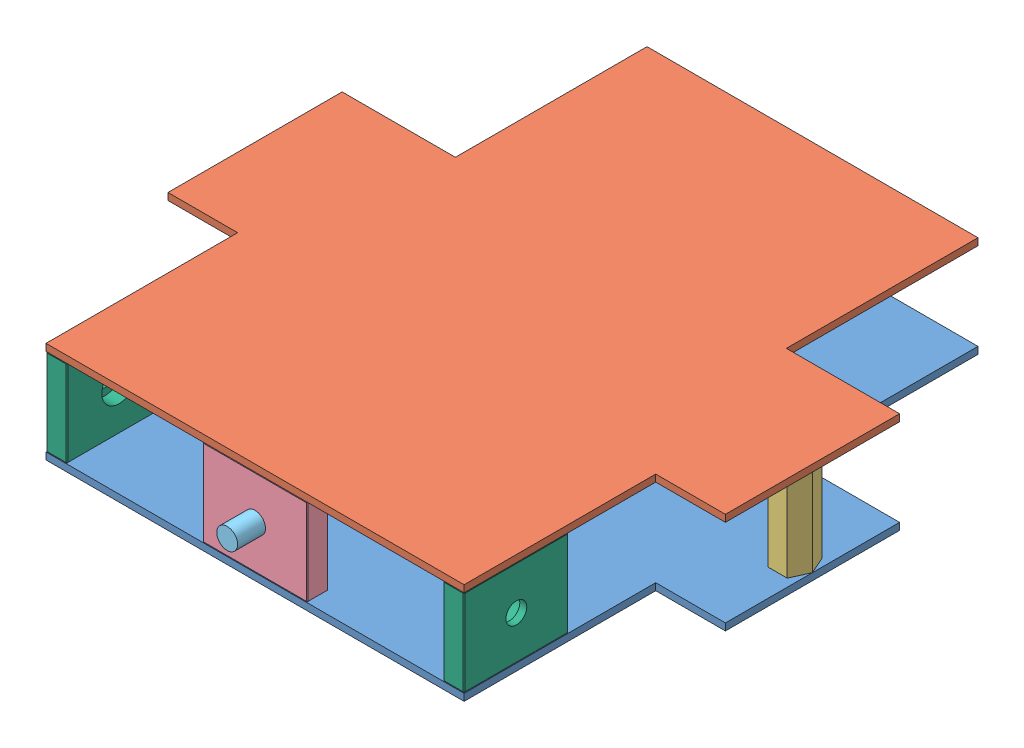
SolidWorks assembly modulo, configuration Default. Lengths in mm.
Overall size (160 29 176).
10 component instances, 6 part files, 25 mates.
Components (placement in the parent):
- chassi_inf-5: chassi_inf [Default] at origin size (160 2 160)
- chassi_sup-5: chassi_sup [Default] at (0 27 0) size (160 2 160)
- espacadores-2: espacadores [Default] at (75 2 0) size (10 25 10)
- apoio_acopolamento-1: apoio_acopolamento [Default] at (0 2 77) size (30 25 6)
- apoio_acopolamento-2: apoio_acopolamento [Default] at (0 2 -77) x (-1 0 0) z (0 0 -1) size (30 25 6)
- espacadores-5: espacadores [Default] at (-75 2 0) size (10 25 10)
- apoio_acopolamento2-1: apoio_acopolamento2 [Default] at (0 14.5 -78) x (0.923728 0.383049 0) z (-0.383049 0.923728 0) size (10 14 10)
- apoio_acopolamento2-2: apoio_acopolamento2 [Default] at (0 14.5 78) x (0.923728 0.383049 0) z (0.383049 -0.923728 0) size (10 14 10)
- apoio_rolamento1-1: apoio_rolamento1 [Default] at (-57 27 65) x (0 0 -1) z (-1 0 0) size (30 25 6)
- apoio_rolamento1-2: apoio_rolamento1 [Default] at (57 27 65) x (0 0 1) z (1 0 0) size (30 25 6)
Mates (geometry in assembly coordinates):
- Coincident39: coincident aligned: plane of chassi_inf-5 through (-47.5 2 -80) normal (0 0 -1); plane of apoio_acopolamento-2 through (15 27 -80) normal (0 0 -1)
- Coincident40: coincident anti-aligned: plane of chassi_inf-5 through (-47.5 2 -25) normal (0 1 0); plane of apoio_acopolamento-2 through (15 2 -80) normal (0 -1 0)
- Coincident41: coincident anti-aligned: plane of chassi_inf-5 through (-47.5 2 -25) normal (0 1 0); plane of espacadores-2 through (67.7429 2 -5) normal (0 -1 0)
- Coincident42: coincident anti-aligned: plane of chassi_inf-5 through (-47.5 2 -25) normal (0 1 0); plane of apoio_acopolamento-1 through (-15 2 80) normal (0 -1 0)
- Coincident43: coincident aligned: plane of chassi_inf-5 through (-60 2 80) normal (0 0 1); plane of apoio_acopolamento-1 through (-15 27 80) normal (0 0 1)
- Width1: width: plane of apoio_acopolamento-1 through (-15 27 74) normal (-1 0 0); plane of apoio_acopolamento-1 through (15 27 74) normal (1 0 0); plane of chassi_inf-5 through (60 2 25) normal (1 0 0); plane of chassi_inf-5 through (-60 2 25) normal (-1 0 0)
- Coincident44: coincident aligned: plane of apoio_acopolamento-1 through (15 27 74) normal (1 0 0); plane of apoio_acopolamento-2 through (15 27 -74) normal (1 0 0)
- Coincident45: coincident anti-aligned: plane of chassi_inf-5 through (-47.5 2 -25) normal (0 1 0); plane of espacadores-5 through (-82.2571 2 -5) normal (0 -1 0)
- Coincident46: coincident anti-aligned: plane of chassi_sup-5 through (-47.5 27 -25) normal (0 -1 0); plane of apoio_acopolamento-2 through (15 27 -80) normal (0 1 0)
- Coincident47: coincident aligned: plane of chassi_inf-5 through (-47.5 2 -80) normal (0 0 -1); plane of chassi_sup-5 through (-47.5 29 -80) normal (0 0 -1)
- Coincident48: coincident aligned: plane of chassi_inf-5 through (47.5 2 -80) normal (1 0 0); plane of chassi_sup-5 through (47.5 29 -80) normal (1 0 0)
- Concentric9: concentric aligned: cylinder of apoio_acopolamento-2; cylinder of apoio_acopolamento2-1
- Coincident49: coincident anti-aligned: plane of apoio_acopolamento-2 through (0 14.5 -78) normal (0 0 1); plane of apoio_acopolamento2-1 through (0 14.5 -78) normal (0 0 -1)
- Concentric10: concentric aligned: cylinder of apoio_acopolamento-1; cylinder of apoio_acopolamento2-2
- Coincident50: coincident anti-aligned: plane of apoio_acopolamento-1 through (0 14.5 78) normal (0 0 -1); plane of apoio_acopolamento2-2 through (0 14.5 78) normal (0 0 1)
- Width3: width: plane of chassi_sup-5 through (-80 29 -25) normal (0 0 -1); plane of chassi_sup-5 through (-80 29 25) normal (0 0 1); plane of espacadores-5 through (-77.7429 27 -5) normal (0 0 -1); plane of espacadores-5 through (-72.2571 27 5) normal (0 0 1)
- Coincident58: coincident: plane of chassi_inf-5 through (-80 2 -25) normal (-1 0 0); line of espacadores-5
- Coincident59: coincident aligned: plane of espacadores-2 through (77.7429 27 5) normal (0 0 1); plane of espacadores-5 through (-72.2571 27 5) normal (0 0 1)
- Coincident60: coincident: plane of chassi_inf-5 through (80 2 -25) normal (1 0 0); line of espacadores-2
- Coincident61: coincident anti-aligned: plane of chassi_inf-5 through (-47.5 2 -25) normal (0 1 0); plane of apoio_rolamento1-1 through (-60 2 80) normal (0 -1 0)
- Coincident62: coincident aligned: plane of chassi_inf-5 through (-60 2 25) normal (-1 0 0); plane of apoio_rolamento1-1 through (-60 2 80) normal (-1 0 0)
- Coincident63: coincident aligned: plane of chassi_inf-5 through (-60 2 80) normal (0 0 1); plane of apoio_rolamento1-1 through (-54 2 80) normal (0 0 1)
- Coincident64: coincident anti-aligned: plane of chassi_inf-5 through (-47.5 2 -25) normal (0 1 0); plane of apoio_rolamento1-2 through (60 2 50) normal (0 -1 0)
- Coincident65: coincident aligned: plane of chassi_inf-5 through (60 2 25) normal (1 0 0); plane of apoio_rolamento1-2 through (60 2 50) normal (1 0 0)
- Coincident66: coincident aligned: plane of chassi_inf-5 through (-60 2 80) normal (0 0 1); plane of apoio_rolamento1-2 through (54 2 80) normal (0 0 1)
